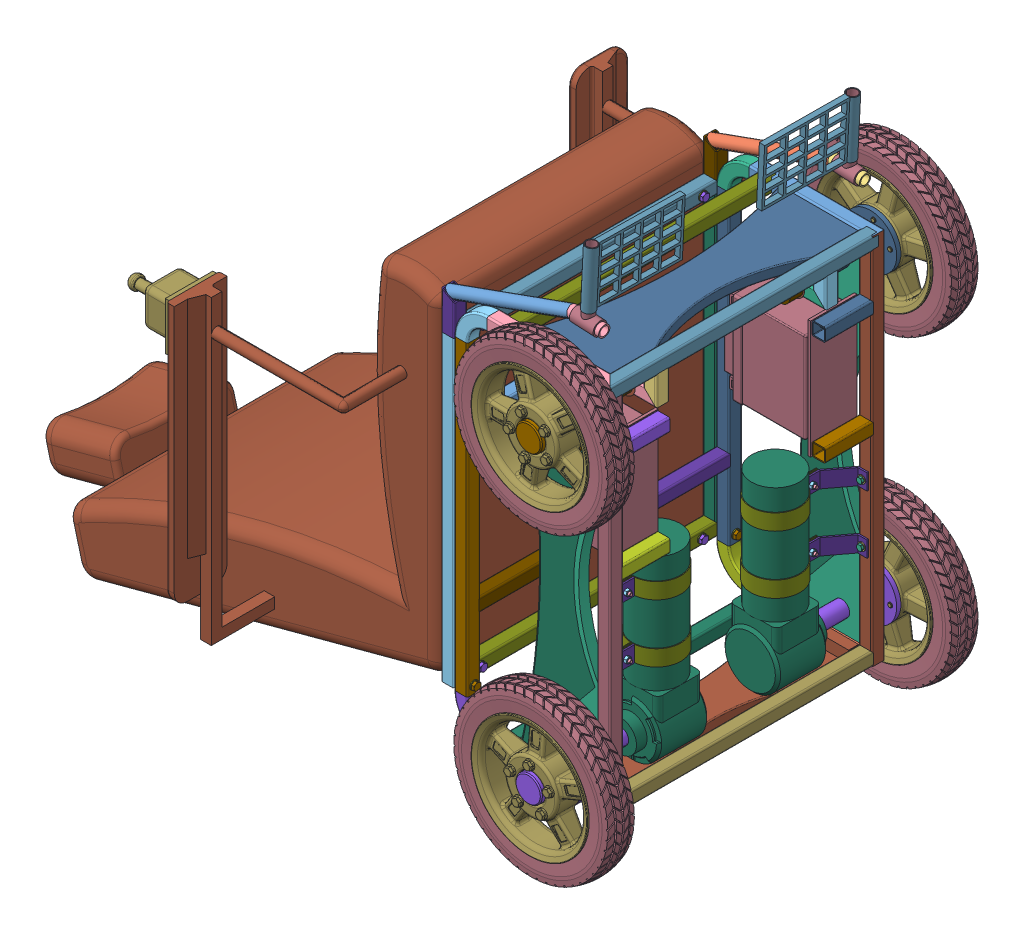
SolidWorks assembly WheelChair, configuration Default. Lengths in mm.
Overall size (1382.08 1057.97 860).
182 component instances, 74 part files, 0 mates.
Components (placement in the parent):
- s_rama_2.0.stp-1: s_rama_2.0.stp [Default] at (-74.1013 396.6742 671.0641) size (295 705 520)
  - Frame0002.stp-1: Frame0002.stp [Default] at origin size (295 705 520)
    - DIN 25 x 25 x 2 00000021.stp-1: DIN 25 x 25 x 2 00000021.stp [Default] at (-133.3987 317.2186 -247.5) x (0 0 -1) z (1 0 0) size (25 25 232.5)
    - DIN 25 x 25 x 2 00000022.stp-1: DIN 25 x 25 x 2 00000022.stp [Default] at (-133.3987 -362.7814 -247.5) x (0 0 -1) z (1 0 0) size (25 25 232.5)
    - DIN 25 x 25 x 2 00000023.stp-1: DIN 25 x 25 x 2 00000023.stp [Default] at (-133.3987 -362.7814 247.5) x (0 0 -1) z (1 0 0) size (25 25 232.5)
    - DIN 25 x 25 x 2 00000024.stp-1: DIN 25 x 25 x 2 00000024.stp [Default] at (-133.3987 317.2186 247.5) x (0 0 -1) z (1 0 0) size (25 25 232.5)
    - DIN 25 x 25 x 2 00000025.stp-1: DIN 25 x 25 x 2 00000025.stp [Default] at (-183.3987 267.2186 247.5) x (0 0 -1) z (0 1 0) size (25 62.5 62.5)
    - DIN 25 x 25 x 2 00000026.stp-1: DIN 25 x 25 x 2 00000026.stp [Default] at (-183.3987 267.2186 -247.5) x (0 0 -1) z (0 1 0) size (25 62.5 62.5)
    - DIN 25 x 25 x 2 00000027.stp-1: DIN 25 x 25 x 2 00000027.stp [Default] at (-183.3987 -312.7814 -247.5) x (0 0 -1) z (0 -1 0) size (25 62.5 62.5)
    - DIN 25 x 25 x 2 00000028.stp-1: DIN 25 x 25 x 2 00000028.stp [Default] at (-183.3987 -312.7814 247.5) x (0 0 -1) z (0 -1 0) size (25 62.5 62.5)
    - DIN 25 x 25 x 2 00000029.stp-1: DIN 25 x 25 x 2 00000029.stp [Default] at (-183.3987 267.2186 247.5) x (0 0 -1) z (0 -1 0) size (25 25 580)
    - DIN 25 x 25 x 2 00000030.stp-1: DIN 25 x 25 x 2 00000030.stp [Default] at (-183.3987 267.2186 -247.5) x (0 0 -1) z (0 -1 0) size (25 25 580)
    - DIN 25 x 25 x 2 00000031.stp-1: DIN 25 x 25 x 2 00000031.stp [Default] at (86.6013 -362.7814 -247.5) x (0 0 -1) z (0 1 0) size (25 25 705)
    - DIN 25 x 25 x 2 00000032.stp-1: DIN 25 x 25 x 2 00000032.stp [Default] at (86.6013 -362.7814 247.5) x (0 -1 0) z (0 0 -1) size (25 25 507.5)
    - DIN 25 x 25 x 2 00000033.stp-1: DIN 25 x 25 x 2 00000033.stp [Default] at (86.6013 317.2186 247.5) x (0 0 1) z (0 -1 0) size (25 25 680)
    - DIN 25 x 25 x 2 00000034.stp-1: DIN 25 x 25 x 2 00000034.stp [Default] at (86.6013 317.2186 -247.5) x (0 1 0) z (0 0 1) size (25 25 507.5)
    - DIN 25 x 25 x 2 00000035.stp-1: DIN 25 x 25 x 2 00000035.stp [Default] at (-103.3987 -362.7814 -247.5) size (25 25 495)
    - DIN 25 x 25 x 2 00000036.stp-1: DIN 25 x 25 x 2 00000036.stp [Default] at (-103.3987 317.2186 -247.5) size (25 25 495)
    - DIN 25 x 25 x 2 00000037.stp-1: DIN 25 x 25 x 2 00000037.stp [Default] at (-183.3987 -172.7814 -247.5) x (0 -1 0) z (0 0 1) size (25 25 247.5)
    - DIN 25 x 25 x 2 00000038.stp-1: DIN 25 x 25 x 2 00000038.stp [Default] at (-183.3987 -172.7814 0) x (0 -1 0) z (0 0 1) size (25 25 247.5)
    - DIN 25 x 25 x 2 00000039.stp-1: DIN 25 x 25 x 2 00000039.stp [Default] at (-183.3987 127.2186 0) x (0 -1 0) z (0 0 1) size (25 25 247.5)
    - DIN 25 x 25 x 2 00000040.stp-1: DIN 25 x 25 x 2 00000040.stp [Default] at (-183.3987 127.2186 -247.5) x (0 -1 0) z (0 0 1) size (25 25 247.5)
    - DIN 25 x 25 x 2 00000041.stp-1: DIN 25 x 25 x 2 00000041.stp [Default] at (86.6013 317.2186 160.145) x (-1 0 0) z (0 -1 0) size (25 25 65)
    - DIN 25 x 25 x 2 00000042.stp-1: DIN 25 x 25 x 2 00000042.stp [Default] at (86.6013 264.7186 160.145) x (0 1 0) z (-1 0 0) size (25.02 25.02 44.4)
    - DIN 25 x 25 x 2 00000043.stp-1: DIN 25 x 25 x 2 00000043.stp [Default] at (86.6013 317.2186 -160.145) x (-1 0 0) z (0 -1 0) size (25 25 65)
    - DIN 25 x 25 x 2 00000044.stp-1: DIN 25 x 25 x 2 00000044.stp [Default] at (86.6013 264.7186 -160.145) x (0 1 0) z (-1 0 0) size (25.02 25.02 44.4)
    - DIN 25 x 25 x 2 00000045.stp-1: DIN 25 x 25 x 2 00000045.stp [Default] at (86.6013 14.2186 247.5) x (-1 0 0) z (0 0 -1) size (25 25 100.5)
    - DIN 25 x 25 x 2 00000046.stp-1: DIN 25 x 25 x 2 00000046.stp [Default] at (86.6013 212.2186 247.5) x (-1 0 0) z (0 0 -1) size (25 25 100.5)
    - DIN 25 x 25 x 2 00000047.stp-1: DIN 25 x 25 x 2 00000047.stp [Default] at (86.6013 14.2186 -247.5) size (25 25 100.5)
    - DIN 25 x 25 x 2 00000048.stp-1: DIN 25 x 25 x 2 00000048.stp [Default] at (86.6013 212.2186 -247.5) size (25 25 100.5)
  - szkic_2.stp-1: szkic_2.stp [Default] at (86.6013 -362.7814 -247.5)
  - tuleja_wału.stp-1: tuleja_wału.stp [Default] at (39.1013 264.7186 -147.645) x (0 0 -1) z (0.565686 -0.824621 0) size (25 40 40)
  - tuleja_wału.stp-2: tuleja_wału.stp [Default] at (39.1013 264.7186 172.645) x (0 0 -1) z (-0.700375 -0.713775 0) size (25 40 40)
  - eBom-prt30.stp-1: eBom-prt30.stp [Default] at origin (suppressed, hidden)
- Large wheel assembly.stp-1: Large wheel assembly.stp [Default] at (-35 661.3928 346.0641) x (0 0 -1) z (0.984136 -0.177414 0) size (56.95 300.96 301.06)
  - rim.stp-1: rim.stp [Default] at origin size (56.95 220 220)
  - Wheel large.stp-1: Wheel large.stp [Default] at origin size (52 300.96 301.06)
  - eBom-prt33.stp-1: eBom-prt33.stp [Default] at origin (suppressed, hidden)
- Large wheel assembly.stp-2: Large wheel assembly.stp [Default] at (-35 661.3928 996.0641) x (0 0 1) z (-0.653506 0.756921 0) size (56.95 300.96 301.06)
  - rim.stp-1: rim.stp [Default] at origin size (56.95 220 220)
  - Wheel large.stp-1: Wheel large.stp [Default] at origin size (52 300.96 301.06)
  - eBom-prt33.stp-1: eBom-prt33.stp [Default] at origin (suppressed, hidden)
- Large wheel assembly.stp-3: Large wheel assembly.stp [Default] at (-35 86.3928 996.0641) x (0 0 1) z (0.797007 0.60397 0) size (56.95 300.96 301.06)
  - rim.stp-1: rim.stp [Default] at origin size (56.95 220 220)
  - Wheel large.stp-1: Wheel large.stp [Default] at origin size (52 300.96 301.06)
  - eBom-prt33.stp-1: eBom-prt33.stp [Default] at origin (suppressed, hidden)
- Large wheel assembly.stp-4: Large wheel assembly.stp [Default] at (-35 86.3928 346.0641) x (0 0 -1) z (-0.056386 -0.998409 0) size (56.95 300.96 301.06)
  - rim.stp-1: rim.stp [Default] at origin size (56.95 220 220)
  - Wheel large.stp-1: Wheel large.stp [Default] at origin size (52 300.96 301.06)
  - eBom-prt33.stp-1: eBom-prt33.stp [Default] at origin (suppressed, hidden)
- mocowanie_fotela_podnozkow.stp-1: mocowanie_fotela_podnozkow.stp [Default] at (-347.6046 814.2619 658.5641) x (-1 0 0) z (0 0 -1) size (296.81 728.39 520)
  - Frame0002-1.stp-1: Frame0002-1.stp [Default] at origin size (296.81 728.39 520)
    - DIN 25 x 25 x 2 00000012.stp-1: DIN 25 x 25 x 2 00000012.stp [Default] at (-65.1046 -155.3691 235) x (1 0 0) z (0 0 -1) size (25.01 25.01 495)
    - DIN 25 x 25 x 2 00000013.stp-1: DIN 25 x 25 x 2 00000013.stp [Default] at (-65.1046 -715.3691 235) x (1 0 0) z (0 1 0) size (25 25 572.5)
    - DIN 25 x 25 x 2 00000014.stp-1: DIN 25 x 25 x 2 00000014.stp [Default] at (-65.1046 -715.3691 -260) size (25 25 520)
    - DIN 25 x 25 x 2 00000015.stp-1: DIN 25 x 25 x 2 00000015.stp [Default] at (-65.1046 -155.3691 -260) x (0.999989 0.004781 0) z (-0.004781 0.999989 0.000001) size (25 25 71.78)
    - DIN 25 x 25 x 2 00000016.stp-1: DIN 25 x 25 x 2 00000016.stp [Default] at (-65.1046 -155.3691 235) x (1 0 0) z (0 1 0) size (25 25 71.83)
    - DIN 21,3 x 2,3 00000025.stp-1: DIN 21,3 x 2,3 00000025.stp [Default] at (-65.4154 -90.3699 -260) x (0 0 1) z (-0.941317 0.337523 0) size (21.3 21.3 249.01)
    - DIN 21,3 x 2,3 00000026.stp-1: DIN 21,3 x 2,3 00000026.stp [Default] at (-287.6074 -10.5859 235) x (0 0 -1) z (0.941315 -0.337529 0) size (21.3 21.3 247.97)
    - DIN 21,3 x 2,3 00000027.stp-1: DIN 21,3 x 2,3 00000027.stp [Default] at (-347.5293 -13.6372 234.7515) x (0.004137 0.00021 -0.999991) z (0.998697 0.050855 0.004142) size (21.3 21.3 62.13)
    - DIN 21,3 x 2,3 00000030.stp-1: DIN 21,3 x 2,3 00000030.stp [Default] at (-288.9276 -10.2246 -259.9999) x (0.002102 0.000106 0.999998) z (-0.998703 -0.050862 0.002104) size (21.3 21.3 62.13)
    - DIN 25 x 25 x 2 00000034-0.stp-1: DIN 25 x 25 x 2 00000034-0.stp [Default] at (-65.1046 -715.3691 -260) x (1 0 0) z (0 1 0) size (25 25 572.5)
  - szkic_mocowanie_fotela.stp-1: szkic_mocowanie_fotela.stp [Default] at (-65.1046 -715.3691 -260)
- sciana_boczna_2.stp-1: sciana_boczna_2.stp [Default] at (-207.5 704.3928 433.0641) x (0 0 -1) z (0 1 0) size (22.78 417.68 655.93)
- sciana_boczna_2.stp-2: sciana_boczna_2.stp [Default] at (-207.5 43.3928 909.0641) x (0 0 1) z (0 -1 0) size (22.78 417.68 655.93)
- DIN 617 - NA4906 - 30 x 47 x 17.stp-1: DIN 617 - NA4906 - 30 x 47 x 17.stp [Default] at (-35 86.3928 931.0641) x (0 0 -1) z (-0.960332 0.278859 0) size (17.79 47.91 47.91)
- DIN 617 - NA4906 - 30 x 47 x 17.stp-2: DIN 617 - NA4906 - 30 x 47 x 17.stp [Default] at (-35 661.3928 931.0641) x (0 0 -1) z (0.690483 0.723348 0) size (17.79 47.91 47.91)
- DIN 617 - NA4906 - 30 x 47 x 17.stp-3: DIN 617 - NA4906 - 30 x 47 x 17.stp [Default] at (-35 661.3928 411.0641) x (0 0 1) z (0.607215 0.794538 0) size (17.79 47.91 47.91)
- DIN 617 - NA4906 - 30 x 47 x 17.stp-4: DIN 617 - NA4906 - 30 x 47 x 17.stp [Default] at (-35 86.3928 411.0641) x (0 0 1) z (0.672788 0.739835 0) size (17.79 47.91 47.91)
- wal_piasta.stp-1: wal_piasta.stp [Default] at (-35 86.3928 971.0641) x (0 0 -1) z (-0.957091 0.289788 0) size (195 100 100)
- wal_piasta_przod_2.stp-1: wal_piasta_przod_2.stp [Default] at (-35 661.3928 971.0641) x (0 0 -1) z (-0.228241 -0.973605 0) size (232.36 100 100)
- wal_piasta.stp-2: wal_piasta.stp [Default] at (-35 86.3928 371.0641) x (0 0 1) z (-0.840873 -0.541233 0) size (195 100 100)
- wal_piasta_przod_1.stp-1: wal_piasta_przod_1.stp [Default] at (-35 661.3928 371.0641) x (0 0 1) z (-0.881145 0.472846 0) size (232.36 100 100)
- fotel.stp-1: fotel.stp [Default] at (-295 89.5986 411.0641) x (0 0 1) z (-1 0 0) size (860 824.45 909.81)
- DIN 6921 - M8 x 60 - A.stp-1: DIN 6921 - M8 x 60 - A.stp [Default] at (-56.8713 54.977 1021.0641) x (0 0 -1) z (0.655104 0.755539 0) size (68.16 18 18)
- DIN 6921 - M8 x 60 - A.stp-2: DIN 6921 - M8 x 60 - A.stp [Default] at (-35.7714 124.6643 1021.0641) x (0 0 -1) z (0.655104 0.755539 0) size (68.16 18 18)
- DIN 6921 - M8 x 60 - A.stp-3: DIN 6921 - M8 x 60 - A.stp [Default] at (1.16 98.953 1021.0641) x (0 0 -1) z (0.655104 0.755539 0) size (68.16 18 18)
- DIN 6921 - M8 x 60 - A.stp-4: DIN 6921 - M8 x 60 - A.stp [Default] at (-11.8805 55.8839 1021.0641) x (0 0 -1) z (0.655104 0.755539 0) size (68.16 18 18)
- DIN 6921 - M8 x 60 - A.stp-5: DIN 6921 - M8 x 60 - A.stp [Default] at (-71.6368 97.4856 1021.0641) x (0 0 -1) z (0.655104 0.755539 0) size (68.16 18 18)
- DIN 6921 - M8 x 60 - A.stp-6: DIN 6921 - M8 x 60 - A.stp [Default] at (-43.7369 624.1239 1021.0641) x (0 0 -1) z (-0.943991 0.329972 0) size (68.16 18 18)
- DIN 6921 - M8 x 60 - A.stp-7: DIN 6921 - M8 x 60 - A.stp [Default] at (-73.1447 658.1853 1021.0641) x (0 0 -1) z (-0.980868 0.194672 0) size (68.16 18 18)
- DIN 6921 - M8 x 60 - A.stp-8: DIN 6921 - M8 x 60 - A.stp [Default] at (-49.8378 696.6793 1021.0641) x (0 0 -1) z (-0.876241 0.481873 0) size (68.16 18 18)
- DIN 6921 - M8 x 60 - A.stp-9: DIN 6921 - M8 x 60 - A.stp [Default] at (-2.255 641.5667 1021.0641) x (0 0 -1) z (-0.864293 0.502989 0) size (68.16 18 18)
- DIN 6921 - M8 x 60 - A.stp-10: DIN 6921 - M8 x 60 - A.stp [Default] at (-6.0256 686.4085 1021.0641) x (0 0 -1) z (-0.965671 0.259769 0) size (68.16 18 18)
- DIN 6921 - M8 x 60 - A.stp-11: DIN 6921 - M8 x 60 - A.stp [Default] at (-28.2087 699.0648 321.0641) x (0 0 1) z (-0.995699 -0.092651 0) size (68.16 18 18)
- DIN 6921 - M8 x 60 - A.stp-12: DIN 6921 - M8 x 60 - A.stp [Default] at (-18.3512 626.9236 321.0641) x (0 0 1) z (-0.99861 0.052715 0) size (68.16 18 18)
- DIN 6921 - M8 x 60 - A.stp-13: DIN 6921 - M8 x 60 - A.stp [Default] at (2.9269 666.5751 321.0641) x (0 0 1) z (-0.999327 0.03669 0) size (68.16 18 18)
- DIN 6921 - M8 x 60 - A.stp-14: DIN 6921 - M8 x 60 - A.stp [Default] at (-68.7296 679.493 321.0641) x (0 0 1) z (-0.998265 0.058887 0) size (68.16 18 18)
- DIN 6921 - M8 x 60 - A.stp-15: DIN 6921 - M8 x 60 - A.stp [Default] at (-62.6373 634.9073 321.0641) x (0 0 1) z (-0.997773 -0.066703 0) size (68.16 18 18)
- DIN 6921 - M8 x 60 - A.stp-16: DIN 6921 - M8 x 60 - A.stp [Default] at (3.2184 84.2343 321.0641) x (0 0 1) z (0.655104 0.755539 0) size (68.16 18 18)
- DIN 6921 - M8 x 60 - A.stp-17: DIN 6921 - M8 x 60 - A.stp [Default] at (-67.188 65.6747 321.0641) x (0 0 1) z (0.655104 0.755539 0) size (68.16 18 18)
- DIN 6921 - M8 x 60 - A.stp-18: DIN 6921 - M8 x 60 - A.stp [Default] at (-25.2426 49.3779 321.0641) x (0 0 1) z (0.655104 0.755539 0) size (68.16 18 18)
- DIN 6921 - M8 x 60 - A.stp-19: DIN 6921 - M8 x 60 - A.stp [Default] at (-21.1371 122.0736 321.0641) x (0 0 1) z (0.655104 0.755539 0) size (68.16 18 18)
- DIN 6921 - M8 x 60 - A.stp-20: DIN 6921 - M8 x 60 - A.stp [Default] at (-64.6506 110.6032 321.0641) x (0 0 1) z (0.655104 0.755539 0) size (68.16 18 18)
- podnozek_gora.stp-1: podnozek_gora.stp [Default] at (-51.6861 803.6813 918.5492) x (0.998703 -0.050862 -0.002104) z (0.002107 0 0.999998) size (45 143.15 26.3)
- podnozek_gora.stp-2: podnozek_gora.stp [Default] at (-53.0063 803.32 423.5931) x (0.998697 -0.050855 0.004142) z (-0.004147 0 0.999991) size (45 143.15 26.3)
- podnozek_dol.stp-1: podnozek_dol.stp [Default] at (-23.9245 932.0075 423.7137) x (-0.050854 -0.998706 -0.000211) z (-0.998683 0.050854 -0.006837) size (110 181 22)
- podnozek_dol.stp-2: podnozek_dol.stp [Default] at (-22.6032 932.3686 918.488) x (-0.050862 -0.998706 0.000107) z (0.998611 -0.050855 0.013794) size (110 181 22)
- silnik_prawy_s.stp-1: silnik_prawy_s.stp [Default] at (-74.8526 138.2253 494.6491) x (0 0 -1) z (0 1 0) size (115 105 344.33)
- obejma_silnika.stp-1: obejma_silnika.stp [Default] at (-35 338.2253 558.5641) x (0 -1 0) z (1 0 0) size (30 126 93)
- silnik_mocowanie.stp-1: silnik_mocowanie.stp [Default] at (-32.5 308.2253 512.1311) x (0 1 0) z (-1 0 0) size (30 76 51.5)
- obejma_silnika.stp-2: obejma_silnika.stp [Default] at (-35 198.2253 558.5641) x (0 1 0) z (-1 0 0) size (30 126 93)
- silnik_mocowanie.stp-2: silnik_mocowanie.stp [Default] at (-32.5 198.2253 512.1311) x (0 1 0) z (-1 0 0) size (30 76 51.5)
- mocowanie_walu.stp-1: mocowanie_walu.stp [Default] at (-35 661.3928 818.7091) x (0 0 -1) z (0.228241 0.973605 0) size (25 35.03 35)
- mocowanie_walu.stp-2: mocowanie_walu.stp [Default] at (-35 661.3928 548.4191) x (0 0 -1) z (-0.881145 0.472846 0) size (25 35.03 35)
- DIN 912 - M5 x 0,8 x 12 x 10.stp-1: DIN 912 - M5 x 0,8 x 12 x 10.stp [Default] at (-49.6041 664.8164 806.2091) x (0.973605 -0.228241 0) z (0.00756 0.032247 0.999451) size (17 8.5 8.5)
- DIN 912 - M5 x 0,8 x 12 x 10.stp-2: DIN 912 - M5 x 0,8 x 12 x 10.stp [Default] at (-20.3959 657.9691 806.2091) x (-0.973605 0.228241 0) z (0.00756 0.032247 0.999451) size (17 8.5 8.5)
- DIN 912 - M5 x 0,8 x 12 x 10.stp-3: DIN 912 - M5 x 0,8 x 12 x 10.stp [Default] at (-27.9073 674.6099 535.9191) x (-0.472846 -0.881145 0) z (-0.014177 0.007608 0.999871) size (17 8.5 8.5)
- DIN 912 - M5 x 0,8 x 12 x 10.stp-4: DIN 912 - M5 x 0,8 x 12 x 10.stp [Default] at (-42.0927 648.1756 535.9191) x (0.472846 0.881145 0) z (-0.014177 0.007608 0.999871) size (17 8.5 8.5)
- silnik_prawy_s.stp-2: silnik_prawy_s.stp [Default] at (4.8526 138.2253 847.4791) x (0 0 1) z (0 1 0) size (115 105 344.33)
- DIN 125-2 - B 10,5A.stp-1: DIN 125-2 - B 10,5A.stp [Default] at (-34 323.2253 495.5641) x (-1 0 0) z (0 0.034019 0.999421) size (2 20 20)
- obejma_silnika.stp-3: obejma_silnika.stp [Default] at (-35 198.2253 783.5641) x (0 1 0) z (1 0 0) size (30 126 93)
- obejma_silnika.stp-4: obejma_silnika.stp [Default] at (-35 308.2253 783.5641) x (0 1 0) z (1 0 0) size (30 126 93)
- silnik_mocowanie.stp-3: silnik_mocowanie.stp [Default] at (-32.5 228.2253 829.9971) x (0 -1 0) z (-1 0 0) size (30 76 51.5)
- silnik_mocowanie.stp-4: silnik_mocowanie.stp [Default] at (-32.5 338.2253 829.9971) x (0 -1 0) z (-1 0 0) size (30 76 51.5)
- DIN 125-2 - B 10,5A.stp-2: DIN 125-2 - B 10,5A.stp [Default] at (-34 323.2253 846.5641) x (-1 0 0) z (0 0.034019 0.999421) size (2 20 20)
- DIN 125-2 - B 10,5A.stp-3: DIN 125-2 - B 10,5A.stp [Default] at (-34 213.2253 846.5641) x (-1 0 0) z (0 0.034019 0.999421) size (2 20 20)
- DIN 125-2 - B 7,4A.stp-1: DIN 125-2 - B 7,4A.stp [Default] at (-37.5 213.2253 846.5641) x (-1 0 0) z (0 0.034019 0.999421) size (1.6 14 14)
- DIN 125-2 - B 7,4A.stp-2: DIN 125-2 - B 7,4A.stp [Default] at (-37.5 323.2253 846.5641) x (-1 0 0) z (0 0.034019 0.999421) size (1.6 14 14)
- DIN 125-2 - B 7,4A.stp-3: DIN 125-2 - B 7,4A.stp [Default] at (-37.5 213.2253 495.5641) x (-1 0 0) z (0 0.034019 0.999421) size (1.6 14 14)
- DIN 125-2 - B 7,4A.stp-4: DIN 125-2 - B 7,4A.stp [Default] at (-37.5 323.2253 495.5641) x (-1 0 0) z (0 0.034019 0.999421) size (1.6 14 14)
- DIN EN 24018 - M6 x 20DIN EN.stp-1: DIN EN 24018 - M6 x 20DIN EN.stp [Default] at (-39.1 213.2253 495.5641) x (1 0 0) z (0 0.034019 0.999421) size (24 11.55 10)
- DIN EN 24018 - M6 x 20DIN EN.stp-2: DIN EN 24018 - M6 x 20DIN EN.stp [Default] at (-39.1 323.2253 495.5641) x (1 0 0) z (0 0.034019 0.999421) size (24 11.55 10)
- DIN EN 24018 - M6 x 20DIN EN.stp-3: DIN EN 24018 - M6 x 20DIN EN.stp [Default] at (-39.1 213.2253 846.5641) x (1 0 0) z (0 0.034019 0.999421) size (24 11.55 10)
- DIN EN 24018 - M6 x 20DIN EN.stp-4: DIN EN 24018 - M6 x 20DIN EN.stp [Default] at (-39.1 323.2253 846.5641) x (1 0 0) z (0 0.034019 0.999421) size (24 11.55 10)
- ISO 4034 - M6DIN EN.stp-1: ISO 4034 - M6DIN EN.stp [Default] at (-23.383 323.2253 846.5581) x (-0.999999 0 0.001027) z (0.000966 0.341412 0.939913) size (6.12 11.55 10)
- ISO 4034 - M6DIN EN.stp-2: ISO 4034 - M6DIN EN.stp [Default] at (-23.383 213.2253 846.5578) x (-0.999999 0 0.001027) z (0.001027 -0.000521 0.999999) size (6.12 11.55 10)
- ISO 4034 - M6DIN EN.stp-3: ISO 4034 - M6DIN EN.stp [Default] at (-23.383 213.2253 495.5704) x (-0.999999 0 -0.001027) z (-0.001027 0.03454 0.999403) size (6.12 11.55 10)
- ISO 4034 - M6DIN EN.stp-4: ISO 4034 - M6DIN EN.stp [Default] at (-23.383 323.2253 495.5704) x (-0.999999 0 -0.001027) z (-0.001027 0.000521 0.999999) size (6.12 11.55 10)
- DIN 125-2 - B 7,4A.stp-5: DIN 125-2 - B 7,4A.stp [Default] at (9.5 323.2253 902.9971) x (0 0 -1) z (0 1 0) size (1.6 14 14)
- DIN 125-2 - B 7,4A.stp-6: DIN 125-2 - B 7,4A.stp [Default] at (9.5 213.2253 902.9971) x (0 0 -1) z (0 1 0) size (1.6 14 14)
- DIN 125-2 - B 7,4A.stp-7: DIN 125-2 - B 7,4A.stp [Default] at (9.5 213.2253 439.1311) x (0 0 1) z (0 1 0) size (1.6 14 14)
- DIN 125-2 - B 7,4A.stp-8: DIN 125-2 - B 7,4A.stp [Default] at (9.5 323.2253 439.1311) x (0 0 1) z (0 1 0) size (1.6 14 14)
- DIN EN 24018 - M6 x 12DIN EN.stp-1: DIN EN 24018 - M6 x 12DIN EN.stp [Default] at (9.5 213.2253 440.7311) x (0 0 -1) z (0 1 0) size (16 11.55 10)
- DIN EN 24018 - M6 x 12DIN EN.stp-2: DIN EN 24018 - M6 x 12DIN EN.stp [Default] at (9.5 323.2253 440.7311) x (0 0 -1) z (0 1 0) size (16 11.55 10)
- DIN EN 24018 - M6 x 12DIN EN.stp-3: DIN EN 24018 - M6 x 12DIN EN.stp [Default] at (9.5 213.2253 901.3971) x (0 0 1) z (0 1 0) size (16 11.55 10)
- DIN EN 24018 - M6 x 12DIN EN.stp-4: DIN EN 24018 - M6 x 12DIN EN.stp [Default] at (9.5 323.2253 901.3971) x (0 0 1) z (0 1 0) size (16 11.55 10)
- DIN 125-2 - B 8,4A.stp-1: DIN 125-2 - B 8,4A.stp [Default] at (-270 658.8928 461.0641) size (1.6 16 16)
- DIN EN 24018 - M8 x 70DIN EN.stp-1: DIN EN 24018 - M8 x 70DIN EN.stp [Default] at (-268.4 658.8928 461.0641) x (-1 0 0) z (0 0 1) size (75.3 15.01 13)
- DIN 125-2 - B 8,4A.stp-2: DIN 125-2 - B 8,4A.stp [Default] at (-270 658.8928 881.0641) size (1.6 16 16)
- DIN 125-2 - B 8,4A.stp-3: DIN 125-2 - B 8,4A.stp [Default] at (-270 648.8928 918.5641) size (1.6 16 16)
- DIN 125-2 - B 8,4A.stp-4: DIN 125-2 - B 8,4A.stp [Default] at (-270 648.8928 423.5641) size (1.6 16 16)
- DIN 125-2 - B 8,4A.stp-5: DIN 125-2 - B 8,4A.stp [Default] at (-245 648.8928 918.5641) size (1.6 16 16)
- DIN 125-2 - B 8,4A.stp-6: DIN 125-2 - B 8,4A.stp [Default] at (-245 98.8928 918.5641) size (1.6 16 16)
- DIN 125-2 - B 8,4A.stp-7: DIN 125-2 - B 8,4A.stp [Default] at (-270 98.8928 463.0641) size (1.6 16 16)
- DIN 125-2 - B 8,4A.stp-8: DIN 125-2 - B 8,4A.stp [Default] at (-270 98.8928 881.0641) size (1.6 16 16)
- DIN 125-2 - B 8,4A.stp-9: DIN 125-2 - B 8,4A.stp [Default] at (-270 98.8928 918.5641) size (1.6 16 16)
- DIN 125-2 - B 8,4A.stp-10: DIN 125-2 - B 8,4A.stp [Default] at (-270 98.8928 423.5641) size (1.6 16 16)
- DIN 125-2 - B 8,4A.stp-11: DIN 125-2 - B 8,4A.stp [Default] at (-245 98.8928 423.5641) size (1.6 16 16)
- DIN 125-2 - B 8,4A.stp-12: DIN 125-2 - B 8,4A.stp [Default] at (-245 648.8928 423.5641) size (1.6 16 16)
- DIN EN 24018 - M8 x 45DIN EN.stp-1: DIN EN 24018 - M8 x 45DIN EN.stp [Default] at (-243.4 98.8928 423.5641) x (-1 0 0) z (0 0 1) size (50.3 15.01 13)
- DIN EN 24018 - M8 x 45DIN EN.stp-2: DIN EN 24018 - M8 x 45DIN EN.stp [Default] at (-243.4 648.8928 423.5641) x (-1 0 0) z (0 0 1) size (50.3 15.01 13)
- DIN EN 24018 - M8 x 70DIN EN.stp-2: DIN EN 24018 - M8 x 70DIN EN.stp [Default] at (-268.4 98.8928 881.0641) x (-1 0 0) z (0 0 1) size (75.3 15.01 13)
- DIN EN 24018 - M8 x 45DIN EN.stp-3: DIN EN 24018 - M8 x 45DIN EN.stp [Default] at (-243.4 98.8928 918.5641) x (-1 0 0) z (0 0 1) size (50.3 15.01 13)
- DIN EN 24018 - M8 x 70DIN EN.stp-3: DIN EN 24018 - M8 x 70DIN EN.stp [Default] at (-268.4 98.8928 463.0641) x (-1 0 0) z (0 0 1) size (75.3 15.01 13)
- DIN EN 24018 - M8 x 45DIN EN.stp-4: DIN EN 24018 - M8 x 45DIN EN.stp [Default] at (-243.4 648.8928 918.5641) x (-1 0 0) z (0 0 1) size (50.3 15.01 13)
- DIN EN 24018 - M8 x 70DIN EN.stp-4: DIN EN 24018 - M8 x 70DIN EN.stp [Default] at (-268.4 658.8928 881.0641) x (-1 0 0) z (0 0 1) size (75.3 15.01 13)
- sciana_przod_tyl.stp-1: sciana_przod_tyl.stp [Default] at (3 704.3928 423.5641) x (0 1 0) z (0 0 1) size (19.09 151.74 471.32)
- sciana_tyl.stp-1: sciana_tyl.stp [Default] at (3 24.3928 918.5641) x (0 -1 0) z (0 0 -1) size (58 156.96 470.1)
- joystick.stp-1: joystick.stp [Default] at (-654.3098 527.1433 1006.0641) size (116 90 90)
- batteri.stp-1: batteri.stp [Default] at (-5 570.5731 447.6211) x (0 -1 0) z (-1 0 0) size (223 100 161)
- batteri.stp-2: batteri.stp [Default] at (-5 449.2124 894.5071) x (0 1 0) z (-1 0 0) size (223 100 161)
- DIN 125-2 - B 8,4A.stp-13: DIN 125-2 - B 8,4A.stp [Default] at (-5 413.3928 459.0641) x (-1 0 0) z (0 0 1) size (1.6 16 16)
- DIN 125-2 - B 8,4A.stp-14: DIN 125-2 - B 8,4A.stp [Default] at (-5 606.3928 507.0641) x (-1 0 0) z (0 0 1) size (1.6 16 16)
- DIN 125-2 - B 8,4A.stp-15: DIN 125-2 - B 8,4A.stp [Default] at (-5 606.3928 459.0641) x (-1 0 0) z (0 0 1) size (1.6 16 16)
- DIN 125-2 - B 8,4A.stp-16: DIN 125-2 - B 8,4A.stp [Default] at (-5 413.3928 507.0641) x (-1 0 0) z (0 0 1) size (1.6 16 16)
- DIN 125-2 - B 8,4A.stp-17: DIN 125-2 - B 8,4A.stp [Default] at (-5 413.3928 835.0641) x (-1 0 0) z (0 0 1) size (1.6 16 16)
- DIN 125-2 - B 8,4A.stp-18: DIN 125-2 - B 8,4A.stp [Default] at (-5 413.3928 883.0641) x (-1 0 0) z (0 0 1) size (1.6 16 16)
- DIN 125-2 - B 8,4A.stp-19: DIN 125-2 - B 8,4A.stp [Default] at (-5 606.3928 835.0641) x (-1 0 0) z (0 0 1) size (1.6 16 16)
- DIN 125-2 - B 8,4A.stp-20: DIN 125-2 - B 8,4A.stp [Default] at (-5 606.3928 883.0641) x (-1 0 0) z (0 0 1) size (1.6 16 16)
- DIN EN 24018 - M8 x 16DIN EN.stp-1: DIN EN 24018 - M8 x 16DIN EN.stp [Default] at (-6.6 413.3928 835.0641) size (21.3 15.01 13)
- DIN EN 24018 - M8 x 16DIN EN.stp-2: DIN EN 24018 - M8 x 16DIN EN.stp [Default] at (-6.6 413.3928 883.0641) size (21.3 15.01 13)
- DIN EN 24018 - M8 x 16DIN EN.stp-3: DIN EN 24018 - M8 x 16DIN EN.stp [Default] at (-6.6 606.3928 835.0641) size (21.3 15.01 13)
- DIN EN 24018 - M8 x 16DIN EN.stp-4: DIN EN 24018 - M8 x 16DIN EN.stp [Default] at (-6.6 606.3928 883.0641) size (21.3 15.01 13)
- DIN EN 24018 - M8 x 16DIN EN.stp-5: DIN EN 24018 - M8 x 16DIN EN.stp [Default] at (-6.6 413.3928 459.0641) size (21.3 15.01 13)
- DIN EN 24018 - M8 x 16DIN EN.stp-6: DIN EN 24018 - M8 x 16DIN EN.stp [Default] at (-6.6 413.3928 507.0641) size (21.3 15.01 13)
- DIN EN 24018 - M8 x 16DIN EN.stp-7: DIN EN 24018 - M8 x 16DIN EN.stp [Default] at (-6.6 606.3928 459.0641) size (21.3 15.01 13)
- DIN EN 24018 - M8 x 16DIN EN.stp-8: DIN EN 24018 - M8 x 16DIN EN.stp [Default] at (-6.6 606.3928 507.0641) size (21.3 15.01 13)
- DIN 125-2 - B 10,5A.stp-4: DIN 125-2 - B 10,5A.stp [Default] at (-34 213.2253 495.5641) x (-1 0 0) z (0 0 1) size (2 20 20)
- maskownica_boczna.stp-1: maskownica_boczna.stp [Default] at (-207.5 43.3928 415.0641) x (0 0 1) z (-1 0 0) size (17 655 141.48)
- maskownica_boczna.stp-2: maskownica_boczna.stp [Default] at (-207.5 43.3928 910.0641) x (0 0 1) z (-1 0 0) size (17 655 141.48)
- eBom-prt73.stp-1: eBom-prt73.stp [Default] at origin (suppressed, hidden)
